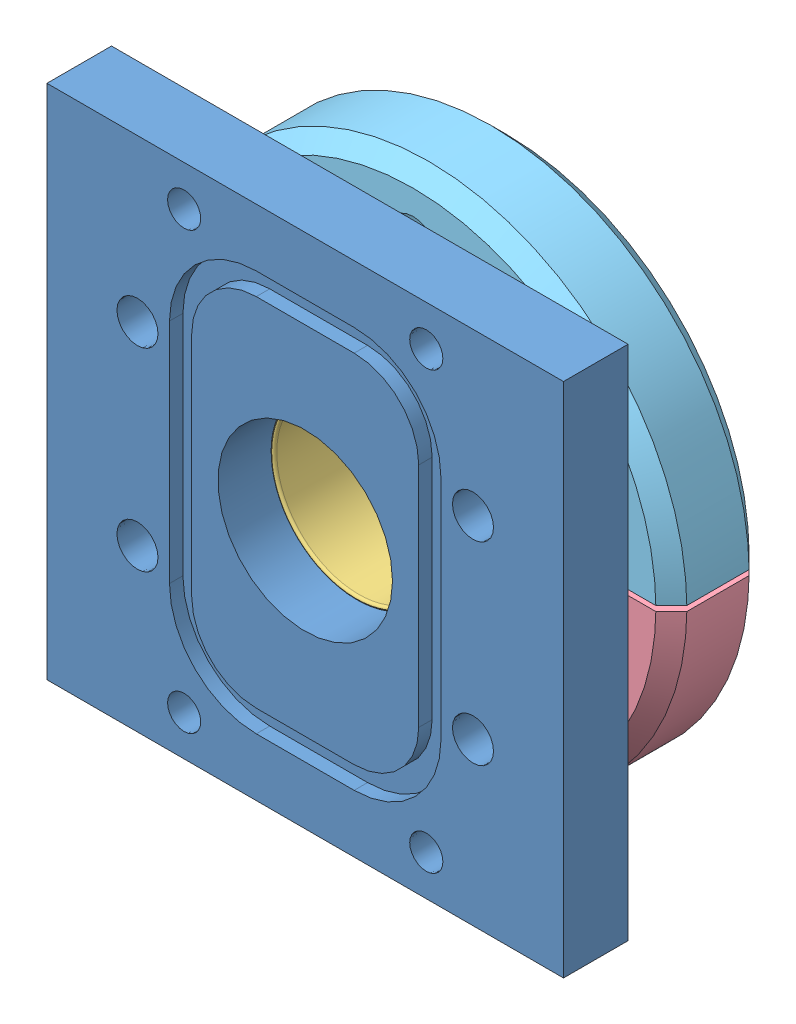
SolidWorks assembly reel_flange_qf16_feedthrough, configuration Default. Lengths in mm.
Overall size (50.8 50.8 24.38).
8 component instances, 6 part files, 7 mates.
Components (placement in the parent):
- reel_housing_to_qf16_flange-1: reel_housing_to_qf16_flange [Default] at (-5.1644 5.2376 -4.0082) size (50.8 50.8 6.35)
- QF16-075-ARB-1: QF16-075-ARB [Default] at (-5.1644 5.2376 -6.6752) x (0.993968 -0.109671 0) z (0.109671 0.993968 0) size (29.08 8 29.08)
  - C0001197-1: C0001197 [Default] x (1 0 0) z (0 1 0) size (29.08 29.08 5.33)
  - P0001219-1: P0001219 [Default] at origin size (19.87 8 19.87)
- QF16-075-BC_1-1: QF16-075-BC_1 [Default] at (-5.1644 5.2376 -8.263) x (0 0 -1) z (0 1 0) size (9.17 50.8 50.8)
  - QF16-075-BC-R_2-1: QF16-075-BC-R_2 [Default] at origin size (9.17 50.8 25.15)
  - QF16-075-BC-R_3-1: QF16-075-BC-R_3 [Default] at origin size (9.17 50.8 25.15)
- QF16-075-VP-1: QF16-075-VP [Default] at (-5.1644 5.2376 -22.0422) x (-1 0 0) z (0 0 -1) size (29.97 29.97 12.7)
Mates (geometry in assembly coordinates):
- Concentric1: concentric aligned: cylinder of QF16-075-BC_1-1/QF16-075-BC-R_3-1 through (-5.1644 5.2376 -17.4324) axis (0 0 -1) radius 11.43; cylinder of QF16-075-VP-1 through (-5.1644 5.2376 -76.0489) axis (0 0 -1) radius 10.9982
- Coincident1: coincident aligned: cone of QF16-075-BC_1-1/QF16-075-BC-R_3-1 through (-5.1644 5.2376 -12.3732) axis (0 0 -1); cone of QF16-075-VP-1 through (-5.1644 5.2376 -13.4587) axis (0 0 -1)
- Concentric3: concentric anti-aligned: cylinder of QF16-075-ARB-1/P0001219-1 through (-5.1644 5.2376 -8.6437) axis (0 0 1) radius 8.509; cylinder of QF16-075-VP-1 through (-5.1644 5.2376 -76.0489) axis (0 0 -1) radius 8.5852
- Tangent1: tangent: torus of QF16-075-ARB-1/C0001197-1; plane of QF16-075-VP-1 through (9.8216 5.2376 -9.3422) normal (0 0 1)
- Concentric4: concentric anti-aligned: cylinder of reel_housing_to_qf16_flange-1 through (-5.1644 5.2376 -4.0082) axis (0 0 1) radius 8.5852; cylinder of QF16-075-ARB-1/P0001219-1 through (-5.1644 5.2376 -4.7067) axis (0 0 -1) radius 8.509
- Concentric7: concentric aligned: cylinder of reel_housing_to_qf16_flange-1 through (11.3334 -4.2874 -4.0082) axis (0 0 -1) radius 2.0193; cylinder of QF16-075-BC_1-1/QF16-075-BC-R_2-1 through (11.3334 -4.2874 -17.4324) axis (0 0 -1) radius 2.413
- Tangent2: tangent: plane of reel_housing_to_qf16_flange-1 through (20.2356 30.6376 -4.0082) normal (0 0 -1); torus of QF16-075-ARB-1/C0001197-1
